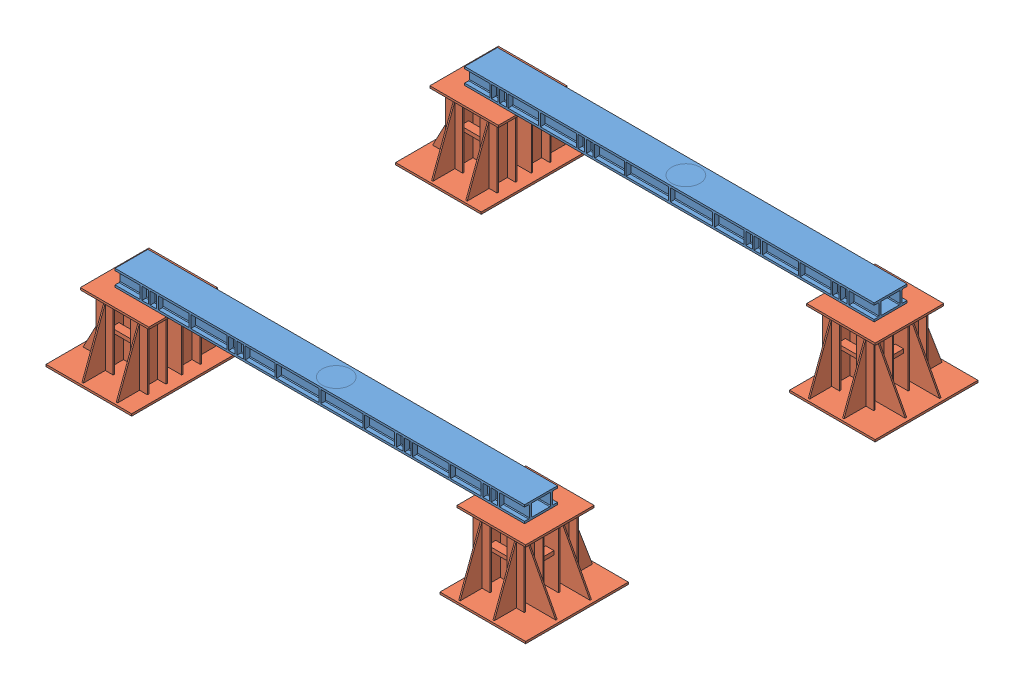
SolidWorks assembly ProjAssem, configuration Default. Lengths in mm.
Overall size (8188.18 2047.1 6602.54).
6 component instances, 2 part files, 5 mates.
Components (placement in the parent):
- BEAM-1: BEAM [Default] at (1217.9111 3287.7287 4606.4323) size (5975 2047.1 480)
- SUPPORT-1: SUPPORT [Default] at (4886.8008 3095.7526 5577.0123) x (-1 0 0) z (0 0 -1) size (1994.98 1000 1500)
- SUPPORT-2: SUPPORT [Default] at (-74.7369 3095.7526 4112.7714) size (1994.98 1000 1500)
- SUPPORT-3: SUPPORT [Default] at (-74.7369 3095.7526 9212.7714) size (1994.98 1000 1500)
- SUPPORT-4: SUPPORT [Default] at (4886.8008 3095.7526 10677.0123) x (-1 0 0) z (0 0 -1) size (1994.98 1000 1500)
- BEAM-2: BEAM [Default] at (1217.9111 3287.7287 9706.4323) size (5975 2047.1 480)
Mates (geometry in assembly coordinates):
- Coincident1: coincident anti-aligned: plane of BEAM-1 through (1217.9111 3125.7526 5086.4323) normal (0 -1 0); plane of SUPPORT-1 through (4886.8008 3125.7526 5577.0123) normal (0 1 0)
- Coincident4: coincident anti-aligned: plane of BEAM-1 through (1217.9111 3125.7526 5086.4323) normal (0 -1 0); plane of SUPPORT-2 through (-74.7369 3125.7526 4112.7714) normal (0 1 0)
- Parallel3: parallel aligned: plane of SUPPORT-1 through (4656.0316 2125.7526 4096.1622) normal (0 0 -1); plane of SUPPORT-2 through (-1093.9677 2125.7526 4093.6215) normal (0 0 -1)
- Distance4: distance = 4500 mm: line of SUPPORT-2 through (156.0323 3125.7526 4343.6215) axis (0 -1 0); line of SUPPORT-1 through (4656.0316 3125.7526 4346.1622) axis (0 -1 0)
- Parallel4: parallel aligned: line of BEAM-1 through (5381.2135 3125.7526 4606.4323) axis (-1 0 0); line of SUPPORT-2 through (156.0323 3125.7526 4343.6215) axis (-1 0 0)
